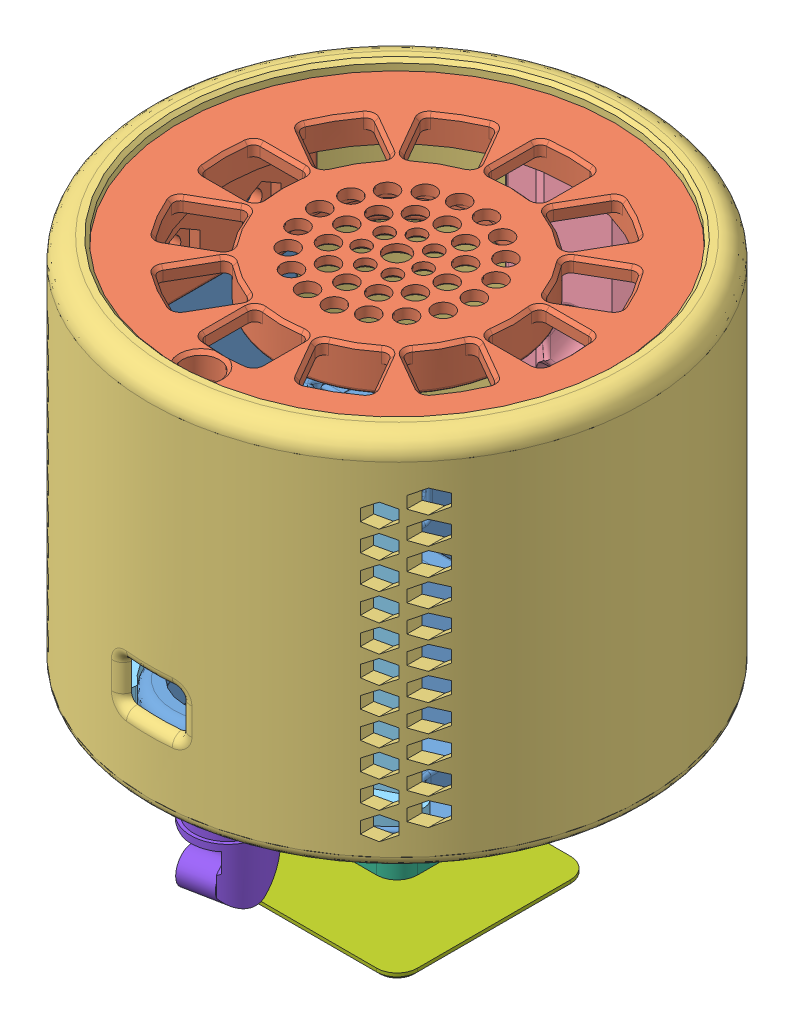
SolidWorks assembly Assem1, configuration Default. Lengths in mm.
Overall size (73.53 81.18 73.53).
9 component instances, 8 part files, 15 mates.
Components (placement in the parent):
- Base-1: Base [Default] at (-36.0801 -13.1712 11.3423) size (70 49.48 70.02)
- Top-2: Top [Default] at (-36.0801 39.811 11.3423) x (1 0 0) z (0 0 -1) size (69.2 16.27 69.2)
- kash-1: kash [Default] at (-36.0801 41.9334 11.3423) x (-0.99999 0 -0.004469) z (-0.004469 0 0.99999) size (73.2 55.1 73.2)
- camera holder-1: camera holder [Default] at (-36.0801 -9.1712 11.3423) size (39 45.8 26.12)
- ArduinoHolder-1: ArduinoHolder [Default] at (-36.0801 -9.1712 11.3423) x (-1 0 0) z (0 0 -1) size (51.96 45 13.85)
- WirelessChargingStand-1: WirelessChargingStand [Default] at (-35.6301 -20.4925 11.7923) x (1 0 0) z (0 0 -1) size (31.1 4.8 31.1)
- WirelessChargingStandEndPart-1: WirelessChargingStandEndPart [Default] at (-35.4551 -38.2448 11.9673) x (-1 0 0) z (0 0 1) size (28.65 1 28.65)
- bearing-1: bearing [Default] at (-36.0801 -40.2361 -13.6577) x (0.987061 0 -0.160343) z (0.160343 0 0.987061) size (11 12.5 11)
- bearing-2: bearing [Default] at (-36.0801 -30.4624 36.3423) x (0.981285 0 -0.192559) z (0.192559 0 0.981285) size (11 12.5 11)
Mates (geometry in assembly coordinates):
- Concentric4: concentric aligned: cylinder of Base-1 through (-36.0801 -9.1712 11.3423) axis (0 -1 0) radius 35; cylinder of kash-1 through (-36.0801 145.4538 11.3423) axis (0 -1 0) radius 35.1
- Concentric6: concentric aligned: cylinder of Base-1 through (-36.0801 -4.1712 -13.6577) axis (0 -1 0) radius 9.5; cylinder of camera holder-1 through (-36.0801 -7.1712 -13.6577) axis (0 -1 0) radius 9.65
- Concentric7: concentric aligned: cylinder of Base-1 through (-36.0801 -9.1712 11.3423) axis (0 -1 0) radius 35; cylinder of camera holder-1 through (-36.0801 -7.1712 11.3423) axis (0 -1 0) radius 35
- Concentric8: concentric anti-aligned: cylinder of Base-1 through (-36.0801 -9.1712 11.3423) axis (0 -1 0) radius 35; cylinder of Top-2 through (-36.0801 27.811 11.3423) axis (0 1 0) radius 34.6
- Concentric9: concentric aligned: cylinder of Base-1 through (-36.0801 -4.1712 36.3423) axis (0 -1 0) radius 9.5; cylinder of ArduinoHolder-1 through (-36.0801 -7.1712 36.3423) axis (0 -1 0) radius 9.5
- Concentric10: concentric aligned: cylinder of Base-1 through (-36.0801 -9.1712 11.3423) axis (0 -1 0) radius 35; cylinder of ArduinoHolder-1 through (-36.0801 35.8288 11.3423) axis (0 -1 0) radius 34.5
- Coincident3: coincident anti-aligned: plane of Base-1 through (-51.0801 -11.1712 26.3423) normal (0 0 -1); plane of WirelessChargingStand-1 through (-50.1801 -23.7925 26.3423) normal (0 0 1)
- Coincident4: coincident anti-aligned: plane of Base-1 through (-21.0801 -11.1712 26.3423) normal (-1 0 0); plane of WirelessChargingStand-1 through (-21.0801 -23.7925 26.3423) normal (1 0 0)
- Coincident5: coincident anti-aligned: plane of WirelessChargingStand-1 through (-50.1301 -23.5925 26.2923) normal (0 0 -1); plane of WirelessChargingStandEndPart-1 through (-24.1301 -39.2448 26.2923) normal (0 0 1)
- Coincident6: coincident anti-aligned: plane of WirelessChargingStand-1 through (-21.1301 -23.5925 26.2923) normal (-1 0 0); plane of WirelessChargingStandEndPart-1 through (-21.1301 -39.2448 0.6423) normal (1 0 0)
- Concentric11: concentric anti-aligned: cylinder of Base-1 through (-36.0801 1.9788 -13.6577) axis (0 -1 0) radius 7.65; cylinder of bearing-1 through (-36.0801 -29.2361 -13.6577) axis (0 1 0) radius 5
- Concentric12: concentric anti-aligned: cylinder of Base-1 through (-36.0801 1.9788 36.3423) axis (0 -1 0) radius 7.65; cylinder of bearing-2 through (-36.0801 -19.4624 36.3423) axis (0 1 0) radius 5
- Coincident7: coincident anti-aligned: plane of Base-1 through (-36.0801 -9.1712 11.3423) normal (0 1 0); plane of camera holder-1 through (-36.0801 -9.1712 11.3423) normal (0 -1 0)
- Coincident8: coincident anti-aligned: plane of Base-1 through (-36.0801 -9.1712 11.3423) normal (0 1 0); plane of ArduinoHolder-1 through (-36.0801 -9.1712 36.3423) normal (0 -1 0)
- Coincident10: coincident anti-aligned: plane of Base-1 through (-7.0801 35.8288 -3.2374) normal (-1 0 0); plane of Top-2 through (-7.0801 23.811 25.8423) normal (1 0 0)
